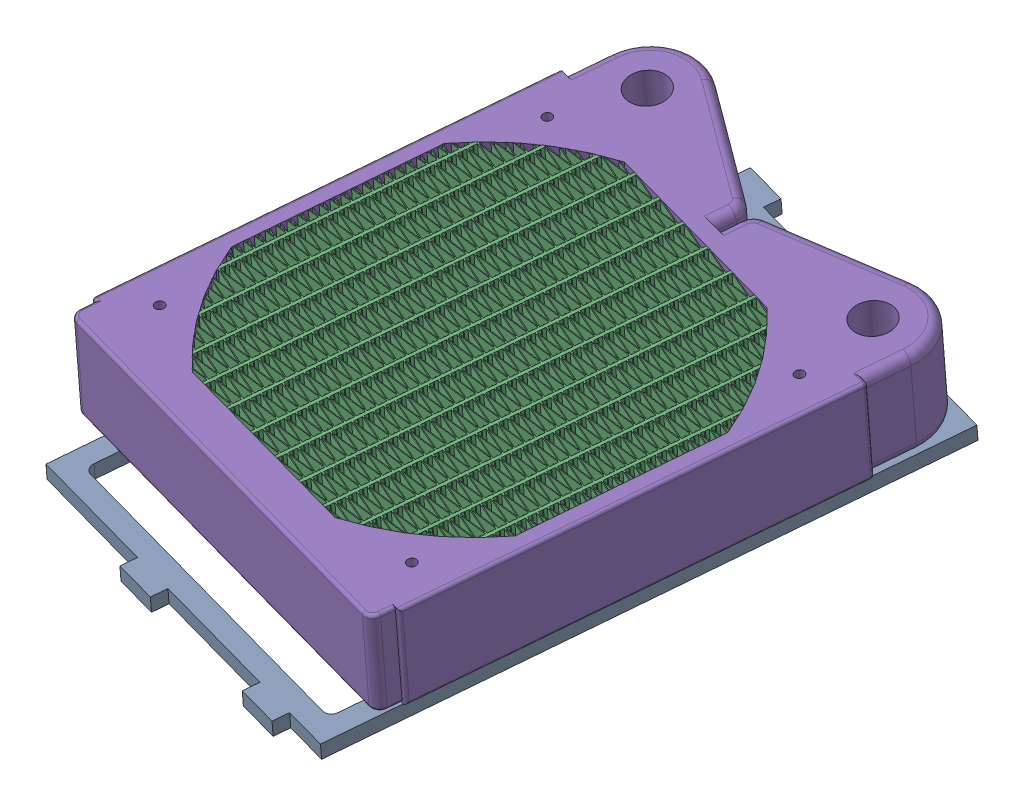
SolidWorks assembly Radiator Panel, configuration Default. Lengths in mm.
Overall size (161.44 73.27 205.59).
6 component instances, 3 part files, 12 mates.
Components (placement in the parent):
- Radiator Panel-1: Radiator Panel [Default] at (-37.0498 33.3786 -16.5806) x (-0.974635 0.090692 -0.204603) z (-0.214715 -0.121053 0.969146) size (114.3 4.76 187.33)
- MCR120-1: MCR120 [Default] at (-52.2029 45.18 60.833) x (0.974635 -0.090692 0.204603) z (-0.214715 -0.121053 0.969146) size (128 30.16 162)
- 0.25in Spacer-1: 0.25in Spacer [Default] at (1.4825 21.4933 51.1953) x (0.997996 -0.063126 -0.004364) z (-0.004364 -0.137455 0.990498) size (6.35 6.35 6.35)
- 0.25in Spacer-2: 0.25in Spacer [Default] at (-100.8541 31.0159 29.712) x (0.997996 -0.063126 -0.004364) z (-0.004364 -0.137455 0.990498) size (6.35 6.35 6.35)
- 0.25in Spacer-3: 0.25in Spacer [Default] at (-78.309 43.7265 -72.0483) x (0.997996 -0.063126 -0.004364) z (-0.004364 -0.137455 0.990498) size (6.35 6.35 6.35)
- 0.25in Spacer-4: 0.25in Spacer [Default] at (24.0276 34.2039 -50.565) x (0.997996 -0.063126 -0.004364) z (-0.004364 -0.137455 0.990498) size (6.35 6.35 6.35)
Mates (geometry in assembly coordinates):
- Concentric1: concentric aligned: circle of Radiator Panel-1; circle of MCR120-1
- Concentric2: concentric anti-aligned: circle of Radiator Panel-1; circle of MCR120-1
- Concentric3: concentric aligned: circle of Radiator Panel-1; circle of MCR120-1
- Concentric4: concentric aligned: circle of Radiator Panel-1; circle of 0.25in Spacer-1
- Coincident2: coincident anti-aligned: plane of Radiator Panel-1 through (-0.4376 17.4339 81.2696) normal (0.063126 0.988494 0.137455); plane of 0.25in Spacer-1 through (1.4825 21.4933 51.1953) normal (-0.063126 -0.988494 -0.137455)
- Concentric5: concentric aligned: circle of Radiator Panel-1; circle of 0.25in Spacer-2
- Coincident3: coincident anti-aligned: plane of Radiator Panel-1 through (-0.4376 17.4339 81.2696) normal (0.063126 0.988494 0.137455); plane of 0.25in Spacer-2 through (-100.8541 31.0159 29.712) normal (-0.063126 -0.988494 -0.137455)
- Concentric6: concentric aligned: circle of Radiator Panel-1; circle of 0.25in Spacer-4
- Coincident4: coincident anti-aligned: plane of Radiator Panel-1 through (-0.4376 17.4339 81.2696) normal (0.063126 0.988494 0.137455); plane of 0.25in Spacer-4 through (24.0276 34.2039 -50.565) normal (-0.063126 -0.988494 -0.137455)
- Concentric7: concentric aligned: circle of Radiator Panel-1; circle of 0.25in Spacer-3
- Coincident5: coincident anti-aligned: plane of Radiator Panel-1 through (-0.4376 17.4339 81.2696) normal (0.063126 0.988494 0.137455); plane of 0.25in Spacer-3 through (-78.309 43.7265 -72.0483) normal (-0.063126 -0.988494 -0.137455)
- Coincident6: coincident anti-aligned: plane of MCR120-1 through (-114.0234 37.0042 38.8925) normal (-0.063126 -0.988494 -0.137455); plane of 0.25in Spacer-2 through (-100.4532 37.2929 30.5848) normal (0.063126 0.988494 0.137455)
